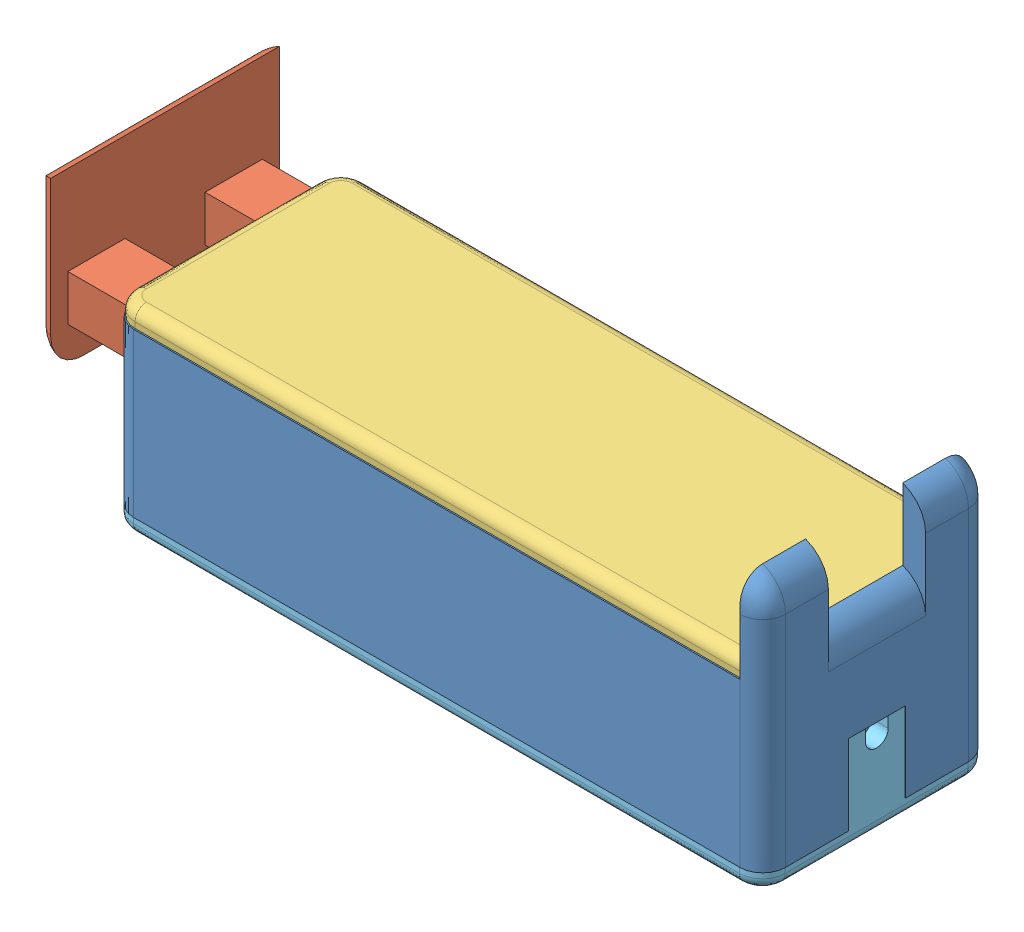
SolidWorks assembly assembly, configuration Default. Lengths in mm.
Overall size (163.21 63.33 51.83).
11 component instances, 8 part files, 32 mates.
Components (placement in the parent):
- body-1: body [Default] at (48.1524 73.359 115.7305) size (144.78 56.51 51.83)
- slider-1: slider [Default] at (-40.1276 92.536 115.7305) x (0 0 -1) z (1 0 0) size (50.8 37.66 91.44)
- spring-cover-1: spring-cover [Default] at (48.1524 91.774 115.4257) size (139.7 3.81 50.8)
- spring-1: spring [Default] at (102.2544 86.3892 129.1216) x (0 -0.455793 -0.890086) z (-1 0 0) size (9.55 9.55 32.26)
- spring-2: spring [Default] at (69.9964 86.3892 102.7543) x (0 -0.759414 -0.650608) z (1 0 0) size (9.55 9.55 32.26)
- sensor-cover-1: sensor-cover [Default] at (50.5336 51.7563 115.6388) size (144.78 21.59 50.8)
- lidar-1: lidar [Default] at (3.7024 71.5329 116.2259) x (0 0 -1) z (-1 0 0) size (42 16.18 15.24)
- nut-M5-1: nut-M5 [Default] at (112.1286 59.6562 101.0338) x (0.866025 0 -0.5) z (0.5 0 0.866025) size (9.02 4 7.81)
- bolt-M5-10mm-1: bolt-M5-10mm [Default] at (112.1286 51.7563 101.0338) x (0.563939 0 -0.825817) z (-0.825817 0 -0.563939) size (10 14.9 10)
- nut-M5-3: nut-M5 [Default] at (-11.0614 59.6562 130.2438) x (0 0 1) z (-1 0 0) size (9.02 4 7.81)
- bolt-M5-10mm-2: bolt-M5-10mm [Default] at (-11.0614 51.7563 130.2438) x (0.395589 0 -0.918428) z (-0.918428 0 -0.395589) size (10 14.9 10)
Mates (geometry in assembly coordinates):
- Tangent1: tangent anti-aligned: cylinder of body-1 through (105.9374 102.1911 102.3955) axis (0 -1 0) radius 3.683; plane of spring-2 through (102.2544 86.3892 102.7543) normal (1 0 0)
- Parallel1: parallel anti-aligned: plane of body-1 through (114.1924 91.774 115.7305) normal (-1 0 0); plane of spring-2 through (102.2544 86.3892 102.7543) normal (1 0 0)
- Tangent2: tangent anti-aligned: plane of body-1 through (48.1524 81.614 115.7305) normal (0 1 0); cylinder of spring-2 through (102.2544 86.3892 102.7543) axis (-1 0 0) radius 4.7752
- Tangent3: tangent anti-aligned: plane of body-1 through (48.1524 81.614 115.7305) normal (0 1 0); cylinder of spring-1 through (69.9964 86.3892 129.1216) axis (1 0 0) radius 4.7752
- Parallel2: parallel anti-aligned: plane of body-1 through (114.1924 91.774 115.7305) normal (-1 0 0); plane of spring-1 through (102.2544 86.3892 129.1216) normal (1 0 0)
- Tangent4: tangent anti-aligned: cylinder of body-1 through (105.9374 102.1911 129.0655) axis (0 -1 0) radius 3.683; plane of spring-1 through (102.2544 86.3892 129.1216) normal (1 0 0)
- Coincident4: coincident anti-aligned: plane of body-1 through (48.1524 91.774 115.7305) normal (0 1 0); plane of spring-cover-1 through (48.1524 91.774 115.4257) normal (0 -1 0)
- Coincident5: coincident anti-aligned: plane of body-1 through (118.0024 73.359 115.7305) normal (-1 0 0); plane of spring-cover-1 through (118.0024 95.584 140.8257) normal (1 0 0)
- Coincident6: coincident anti-aligned: plane of body-1 through (48.1524 81.614 115.7305) normal (0 1 0); plane of slider-1 through (41.1524 81.614 137.3205) normal (0 -1 0)
- Coincident7: coincident anti-aligned: plane of body-1 through (48.1524 91.774 137.3205) normal (0 0 -1); plane of slider-1 through (41.1524 91.774 137.3205) normal (0 0 1)
- LimitDistance1: limit distance = 13.35 mm anti-aligned: plane of slider-1 through (-35.0476 92.536 115.7305) normal (1 0 0); plane of body-1 through (-21.6976 81.614 141.1305) normal (-1 0 0)
- LimitDistance3: limit distance = 59.04 mm anti-aligned: plane of slider-1 through (41.1524 92.536 115.7305) normal (-1 0 0); plane of body-1 through (-17.8876 91.774 115.7305) normal (1 0 0)
- Parallel3: parallel anti-aligned: plane of body-1 through (48.1524 73.359 115.7305) normal (0 -1 0); plane of lidar-1 through (3.7024 71.5329 116.2259) normal (0 1 0)
- Parallel4: parallel anti-aligned: plane of body-1 through (-17.8876 55.579 137.3205) normal (1 0 0); plane of lidar-1 through (-3.9176 60.3569 99.7159) normal (-1 0 0)
- Coincident20: coincident anti-aligned: plane of body-1 through (-3.9176 35.8224 137.3205) normal (1 0 0); plane of lidar-1 through (-3.9176 60.3569 99.7159) normal (-1 0 0)
- Parallel6: parallel anti-aligned: plane of body-1 through (48.1524 55.579 115.7305) normal (0 -1 0); plane of bolt-M5-10mm-1 through (112.1286 51.7563 101.0338) normal (0 1 0)
- Concentric2: concentric aligned: cylinder of sensor-cover-1 through (112.1286 73.3463 101.0338) axis (0 -1 0) radius 2.794; cylinder of bolt-M5-10mm-1 through (112.1286 63.6562 101.0338) axis (0 -1 0) radius 2.5
- Coincident41: coincident anti-aligned: plane of sensor-cover-1 through (50.5336 51.7563 115.6388) normal (0 -1 0); plane of bolt-M5-10mm-1 through (112.1286 51.7563 101.0338) normal (0 1 0)
- Concentric6: concentric aligned: cylinder of sensor-cover-1 through (-11.0614 73.3463 130.2438) axis (0 -1 0) radius 2.794; cylinder of bolt-M5-10mm-2 through (-11.0614 63.6562 130.2438) axis (0 -1 0) radius 2.5
- Coincident44: coincident anti-aligned: plane of sensor-cover-1 through (50.5336 51.7563 115.6388) normal (0 -1 0); plane of bolt-M5-10mm-2 through (-11.0614 51.7563 130.2438) normal (0 1 0)
- Concentric7: concentric aligned: cylinder of nut-M5-1 through (112.1286 63.6562 101.0338) axis (0 -1 0) radius 2.5; cylinder of bolt-M5-10mm-1 through (112.1286 63.6562 101.0338) axis (0 -1 0) radius 2.5
- Concentric8: concentric aligned: cylinder of nut-M5-1 through (112.1286 63.6562 101.0338) axis (0 -1 0) radius 2.5; cylinder of bolt-M5-10mm-1 through (112.1286 63.6562 101.0338) axis (0 -1 0) radius 2.5
- Concentric9: concentric aligned: cylinder of nut-M5-3 through (-11.0614 63.6562 130.2438) axis (0 -1 0) radius 2.5; cylinder of bolt-M5-10mm-2 through (-11.0614 63.6562 130.2438) axis (0 -1 0) radius 2.5
- Coincident47: coincident anti-aligned: plane of body-1 through (48.1524 63.6562 115.7305) normal (0 -1 0); plane of nut-M5-3 through (-11.0614 63.6562 130.2438) normal (0 1 0)
- Parallel7: parallel anti-aligned: plane of body-1 through (-14.9666 63.6562 132.6818) normal (1 0 0); plane of nut-M5-3 through (-14.9666 63.6562 127.9891) normal (-1 0 0)
- Parallel8: parallel anti-aligned: plane of body-1 through (-6.8386 63.6562 132.6818) normal (-0.5 0 -0.866025); plane of nut-M5-3 through (-11.0614 63.6562 134.7532) normal (0.5 0 0.866025)
- Parallel9: parallel anti-aligned: plane of body-1 through (-10.9026 63.6562 125.6428) normal (-0.5 0 0.866025); plane of nut-M5-3 through (-7.1561 63.6562 127.9891) normal (0.5 0 -0.866025)
- Coincident51: coincident anti-aligned: plane of body-1 through (-14.9666 63.6562 132.6818) normal (1 0 0); plane of nut-M5-3 through (-14.9666 63.6562 127.9891) normal (-1 0 0)
- Coincident52: coincident anti-aligned: plane of body-1 through (-14.9666 63.6562 127.9891) normal (0.5 0 0.866025); plane of nut-M5-3 through (-11.0614 63.6562 125.7344) normal (-0.5 0 -0.866025)
- Coincident53: coincident anti-aligned: plane of body-1 through (108.2234 63.6562 103.4718) normal (1 0 0); plane of nut-M5-1 through (108.2234 63.6562 98.7791) normal (-1 0 0)
- Coincident54: coincident anti-aligned: plane of body-1 through (48.1524 63.6562 115.7305) normal (0 -1 0); plane of nut-M5-1 through (112.1286 63.6562 101.0338) normal (0 1 0)
- LimitDistance5: limit distance = 0 mm anti-aligned: plane of bolt-M5-10mm-1 through (112.1286 63.6562 101.0338) normal (0 1 0); plane of body-1 through (48.1524 63.6562 115.7305) normal (0 -1 0)
